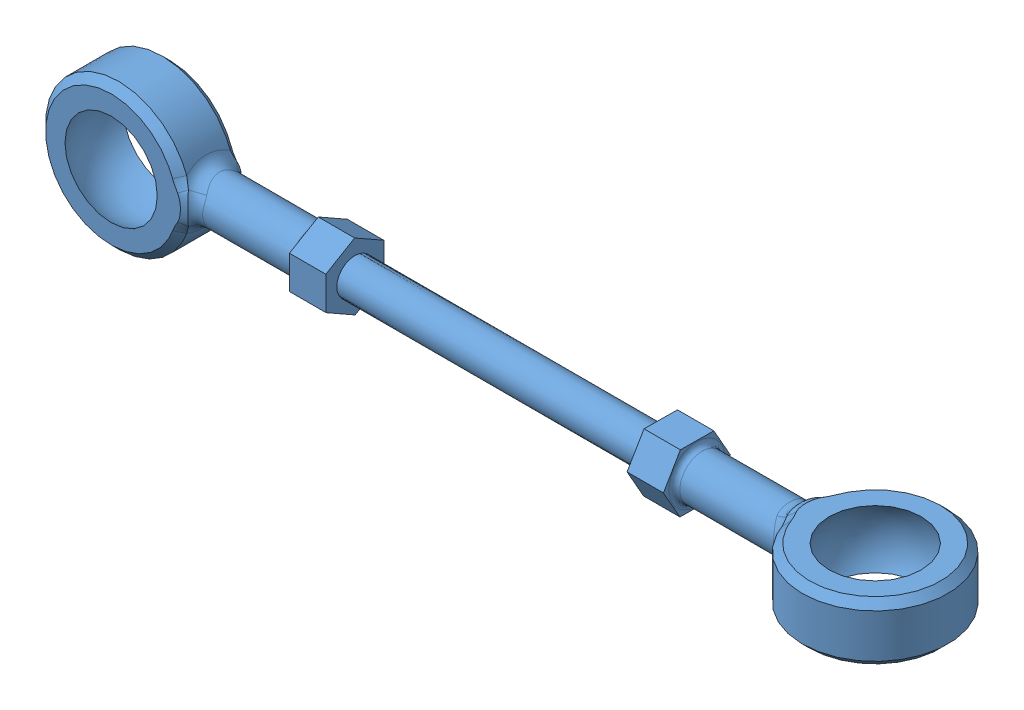
SolidWorks assembly Bivot Nail, configuration Default. Lengths in mm.
Overall size (121.01 20 20).
2 component instances, 1 part files, 4 mates.
Components (placement in the parent):
- Bivot Ball holder-1: Bivot Ball holder [Default] at (80.2414 50.3671 59.847) x (0 0 -1) z (0 -1 0) size (20 89.51 8)
- Bivot Ball holder-2: Bivot Ball holder [Default] at (-20.7734 50.3671 59.847) x (0 1 0) z (0 0 1) size (20 89.51 8)
Mates (geometry in assembly coordinates):
- Concentric3: concentric anti-aligned: cylinder of Bivot Ball holder-1 through (0.734 50.3671 59.847) axis (1 0 0) radius 2.5; cylinder of Bivot Ball holder-2 through (58.734 50.3671 59.847) axis (-1 0 0) radius 2.5
- Parallel1: parallel aligned: plane of Bivot Ball holder-2 through (-20.7734 50.3671 63.847) normal (0 0 1)
- Perpendicular1: perpendicular: plane of Bivot Ball holder-1 through (80.2414 54.3671 59.847) normal (0 1 0); plane of Bivot Ball holder-2 through (-20.7734 50.3671 63.847) normal (0 0 1)
- Coincident2: coincident anti-aligned: plane of Bivot Ball holder-2 through (8.734 50.3671 59.847) normal (1 0 0)
